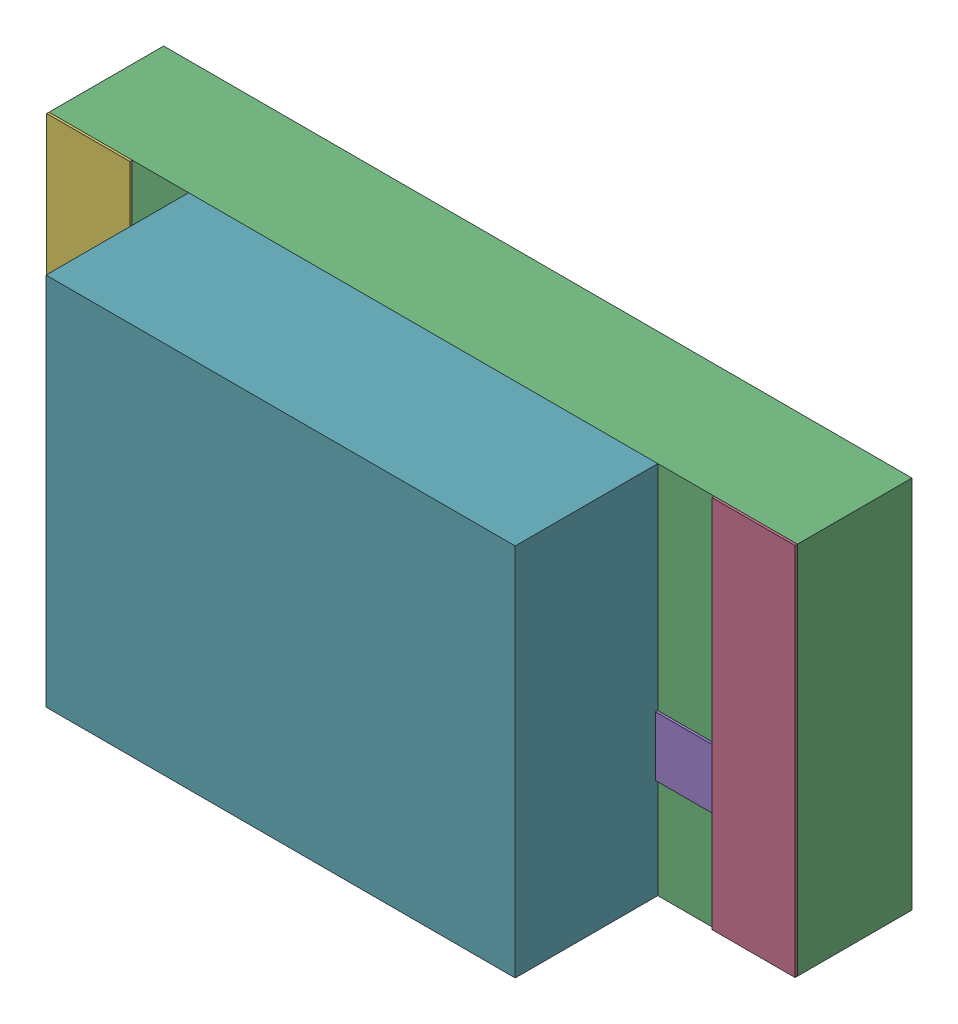
SolidWorks assembly SW3dPS-LED1206R, configuration Défaut. Lengths in mm.
Overall size (3.2 1.6 1.52).
14 component instances, 6 part files, 0 mates.
Components (placement in the parent):
- SW3dPS-LED1206R_Board-1: SW3dPS-LED1206R_Board [Défaut] at (0 0 -0.4039) size (0.03 0.03 0.42)
- SW3dPS-LED1206R_Open_CASCADE_STEP_translator_6.2_278.2-1: SW3dPS-LED1206R_Open_CASCADE_STEP_translator_6.2_278.2 [Défaut] at origin size (3.2 1.6 1.1)
  - SW3dPS-LED1206R_352699472-1: SW3dPS-LED1206R_352699472 [Défaut] at (0.6096 0.0254 0.5027) size (0.65 0.76 0.01)
    - SW3dPS-LED1206R_Extruded3-1: SW3dPS-LED1206R_Extruded3 [Défaut] at origin size (0.65 0.76 0.01)
  - SW3dPS-LED1206R_352697936-1: SW3dPS-LED1206R_352697936 [Défaut] at (1.524 0.0127 0.0127) size (3.2 1.6 0.49)
    - SW3dPS-LED1206R_Extruded1-1: SW3dPS-LED1206R_Extruded1 [Défaut] at origin size (3.2 1.6 0.49)
  - SW3dPS-LED1206R_352697808-1: SW3dPS-LED1206R_352697808 [Défaut] at (2.9464 0.0127 0.5027) size (0.36 1.6 0.01)
    - SW3dPS-LED1206R_Extruded-1: SW3dPS-LED1206R_Extruded [Défaut] at origin size (0.36 1.6 0.01)
  - SW3dPS-LED1206R_352698192-1: SW3dPS-LED1206R_352698192 [Défaut] at (2.1971 0.0254 0.5027) size (1.14 0.76 0.01)
    - SW3dPS-LED1206R_Extruded4-1: SW3dPS-LED1206R_Extruded4 [Défaut] at origin size (1.14 0.76 0.01)
  - SW3dPS-LED1206R_352697808-2: SW3dPS-LED1206R_352697808 [Défaut] at (0.1016 0.0127 0.5027) size (0.36 1.6 0.01)
    - SW3dPS-LED1206R_Extruded-1: SW3dPS-LED1206R_Extruded [Défaut] at origin size (0.36 1.6 0.01)
  - SW3dPS-LED1206R_352701008-1: SW3dPS-LED1206R_352701008 [Défaut] at (1.524 0.0127 0.5027) size (2.01 1.6 0.61)
    - SW3dPS-LED1206R_Extruded2-1: SW3dPS-LED1206R_Extruded2 [Défaut] at origin size (2.01 1.6 0.61)
